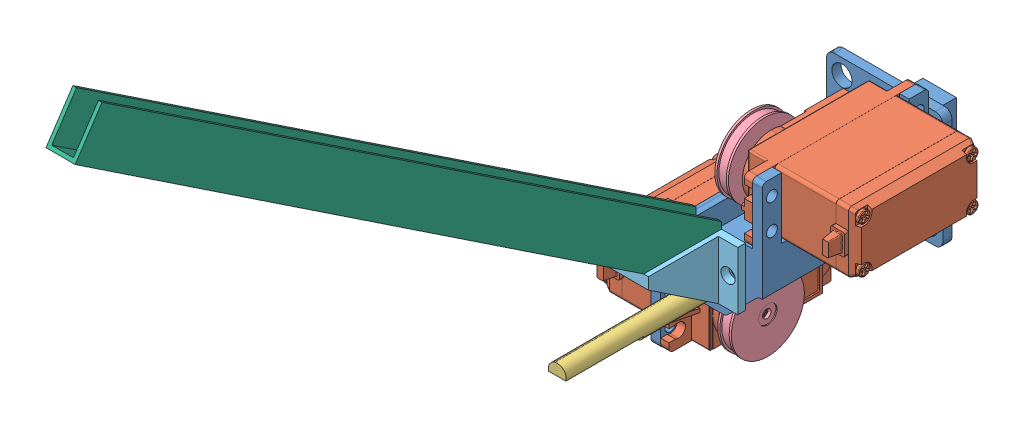
SolidWorks assembly FeederAssem, configuration Default. Lengths in mm.
Overall size (84.05 186.74 289.54).
9 component instances, 6 part files, 15 mates.
Components (placement in the parent):
- JawFeederV3-1: JawFeederV3 [Default] at (34.0119 43.5394 55.6257) size (38.1 63.35 76.17)
- FeederServo-1: FeederServo [Default] at (41.3369 68.5394 104.6757) x (0 0 -1) z (-1 0 0) size (54.3 20 43.9)
- FeederServo-2: FeederServo [Default] at (33.6869 25.1894 104.6757) x (0 0 -1) z (1 0 0) size (54.3 20 43.9)
- DropRod-1: DropRod [Default] at (37.4729 40.1104 53.6257) x (1 0 0) z (0 -1 0) size (5.84 127 5.84)
- DriverWheel-1: DriverWheel [Default] at (36.7159 68.5394 114.5257) x (0 -0.996803 -0.079903) z (0 -0.079903 0.996803) size (23.88 4.83 23.88)
- DriverWheel-2: DriverWheel [Default] at (38.3079 25.1894 114.5257) x (0 -0.399681 0.916654) z (0 -0.916654 -0.399681) size (23.88 4.83 23.88)
- ConnectBowlDescrambler-1: ConnectBowlDescrambler [Default] at (28.9106 72.2688 126.8497) x (1 0 0) z (0 -1 0) size (25.4 220.15 156.23)
  - RampHolder-1: RampHolder [Default] at (-4.0903 4.976 32.2828) size (25.4 25.4 19.05)
  - JawTrack-1: JawTrack [9001K707] at (8.6732 110.6464 -40.2866) x (-1 0 0) z (0 -0.83205 0.5547) size (9.53 15.88 254)
Mates (geometry in assembly coordinates):
- Coincident1: coincident anti-aligned: plane of JawFeederV3-1 through (52.5369 78.5394 131.8257) normal (-1 0 0); plane of FeederServo-1 through (52.5369 60.0394 79.0257) normal (1 0 0)
- Coincident5: coincident aligned: plane of JawFeederV3-1 through (34.0119 78.5394 55.6257) normal (0 1 0); plane of FeederServo-1 through (49.8369 78.5394 79.0257) normal (0 1 0)
- Coincident6: coincident aligned: plane of JawFeederV3-1 through (34.0119 43.5394 131.8257) normal (0 0 1); plane of FeederServo-1 through (49.8369 77.0394 131.8257) normal (0 0 1)
- Coincident7: coincident anti-aligned: plane of JawFeederV3-1 through (22.4869 15.1894 131.8257) normal (1 0 0); plane of FeederServo-2 through (22.4869 33.6894 79.0257) normal (-1 0 0)
- Coincident8: coincident aligned: plane of JawFeederV3-1 through (34.0119 43.5394 131.8257) normal (0 0 1); plane of FeederServo-2 through (25.1869 16.6894 131.8257) normal (0 0 1)
- Coincident9: coincident aligned: plane of JawFeederV3-1 through (34.0119 15.1894 55.6257) normal (0 -1 0); plane of FeederServo-2 through (25.1869 15.1894 79.0257) normal (0 -1 0)
- Concentric1: concentric anti-aligned: circle of JawFeederV3-1; cylinder of DropRod-1 through (37.4729 40.1104 180.6257) axis (0 0 -1) radius 2.921
- Coincident10: coincident: plane of JawFeederV3-1 through (34.0119 43.5394 53.6257) normal (0 0 -1); plane of DropRod-1 through (37.4729 40.1104 53.6257) normal (0 0 -1)
- Coincident11: coincident anti-aligned: plane of FeederServo-1 through (39.6369 68.5394 114.5257) normal (-1 0 0); plane of DriverWheel-1 through (39.6369 68.5394 114.5257) normal (1 0 0)
- Concentric3: concentric aligned: circle of FeederServo-2; cylinder of DriverWheel-2 through (35.3869 25.1894 114.5257) axis (1 0 0) radius 11.938
- Coincident12: coincident anti-aligned: plane of FeederServo-2 through (35.3869 25.1894 114.5257) normal (1 0 0); plane of DriverWheel-2 through (35.3869 25.1894 114.5257) normal (-1 0 0)
- Coincident13: coincident anti-aligned: plane of JawFeederV3-1 through (34.0119 43.5394 131.8257) normal (0 0 1); plane of ConnectBowlDescrambler-1/RampHolder-1 through (24.8203 39.9859 131.8257) normal (0 0 -1)
- Coincident14: coincident anti-aligned: line of JawFeederV3-1 through (34.0119 43.5394 131.8257) axis (1 0 0); line of ConnectBowlDescrambler-1/JawTrack-1 through (41.1557 43.5394 131.8257) axis (-1 0 0)
- Coincident15: coincident aligned: plane of JawFeederV3-1 through (34.0119 43.5394 131.8257) normal (1 0 0); plane of ConnectBowlDescrambler-1/JawTrack-1 through (34.0119 55.3173 123.0199) normal (1 0 0)
- Concentric4: concentric anti-aligned: circle of FeederServo-1; cylinder of DriverWheel-1 through (35.5094 68.5394 114.5257) axis (1 0 0) radius 11.303
